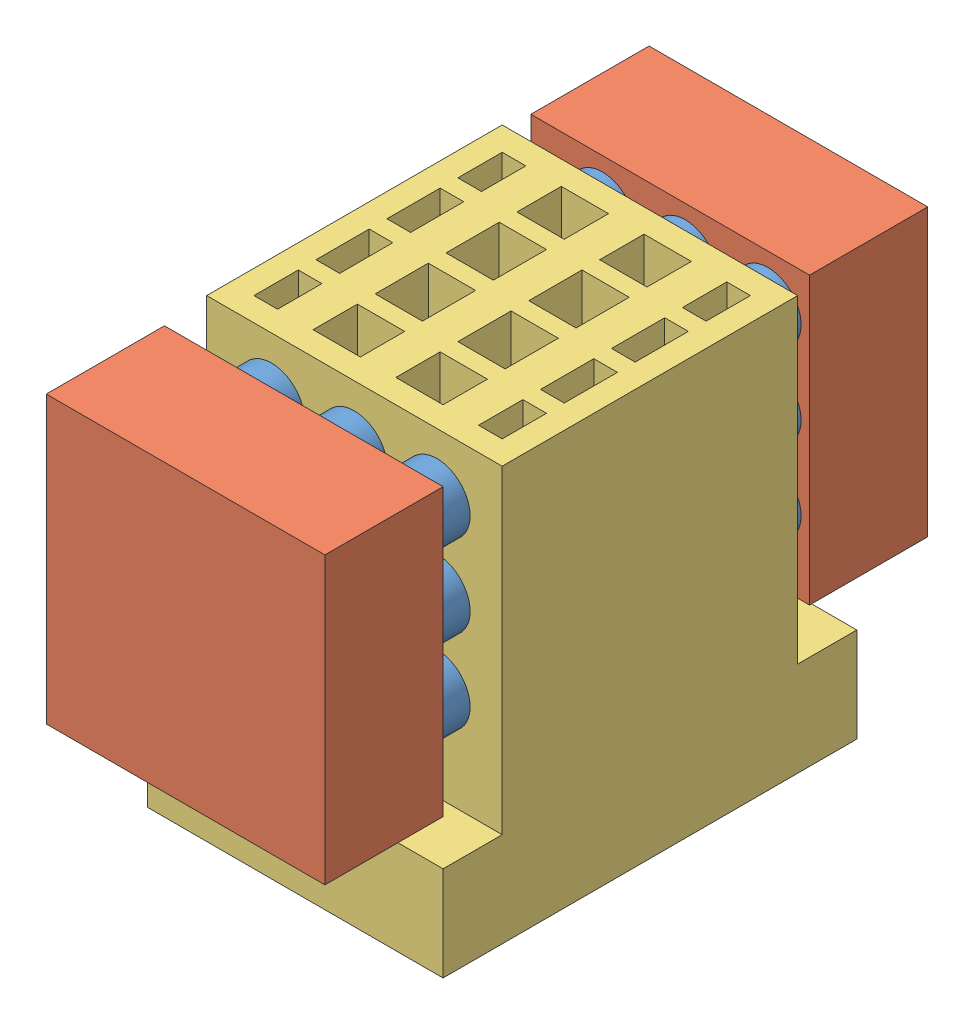
SolidWorks assembly 2.5ellipse, configuration Default. Lengths in mm.
Overall size (50.01 35 51).
5 component instances, 3 part files, 9 mates.
Components (placement in the parent):
- sensor cyli bump-1: sensor cyli bump [Default] at (-61.1671 3.1775 4.2757) size (50 30 3)
- sensorbase-1: sensorbase [Default] at (-61.1754 2.3323 17.2757) size (23.58 24.17 10)
- sensor cyli bump-2: sensor cyli bump [Default] at (-61.1671 3.1775 -23.7243) size (50 30 3)
- sensorbase-2: sensorbase [Default] at (-61.1754 2.3323 -23.7243) size (23.58 24.17 10)
- 3-长方形-1: 3-长方形 [默认] at (-72.6159 -9.5375 1.7757) x (1 0 0) z (0 1 0) size (25 35 35)
Mates (geometry in assembly coordinates):
- 重合5: coincident anti-aligned: plane of sensor cyli bump-1 through (-79.6308 -3.5375 17.2757) normal (0 0 1); plane of sensorbase-1 through (-61.1754 2.3323 17.2757) normal (0 0 -1)
- 同心1: concentric aligned: cylinder of sensor cyli bump-1 through (-79.6308 10.4625 17.2757) axis (0 0 -1) radius 2.8; cylinder of sensor cyli bump-2 through (-79.6308 10.4625 -10.7243) axis (0 0 -1) radius 2.8
- 同心2: concentric aligned: cylinder of sensor cyli bump-1 through (-79.6308 -3.5375 17.2757) axis (0 0 -1) radius 2.8; cylinder of sensor cyli bump-2 through (-79.6308 -3.5375 -10.7243) axis (0 0 -1) radius 2.8
- 重合8: coincident anti-aligned: plane of sensor cyli bump-2 through (-85.6797 -14.6932 -13.7243) normal (0 0 -1); plane of sensorbase-2 through (-61.1754 2.3323 -13.7243) normal (0 0 1)
- 重合11: coincident aligned: plane of sensorbase-1 through (-85.6879 14.4617 27.2757) normal (-1 0 0); plane of sensorbase-2 through (-85.6879 14.4617 -13.7243) normal (-1 0 0)
- 重合12: coincident aligned: plane of sensorbase-1 through (-85.6879 14.4617 27.2757) normal (0 1 0); plane of sensorbase-2 through (-85.6879 14.4617 -13.7243) normal (0 1 0)
- 重合13: coincident: plane of sensor cyli bump-1 through (-85.6797 -14.6932 14.2757) normal (0 0 -1); plane of 3-长方形-1 through (-85.1159 17.1907 14.2757) normal (0 0 1)
- 重合14: coincident: line of sensor cyli bump-1 through (-79.6308 7.6625 14.2757) axis (0 1 0); line of 3-长方形-1 through (-79.6308 15.4625 14.2757) axis (0 -1 0)
- 重合15: coincident aligned: line of sensor cyli bump-1 through (-85.6797 10.4625 14.2757) axis (1 0 0); line of 3-长方形-1 through (-85.1159 10.4625 14.2757) axis (1 0 0)
